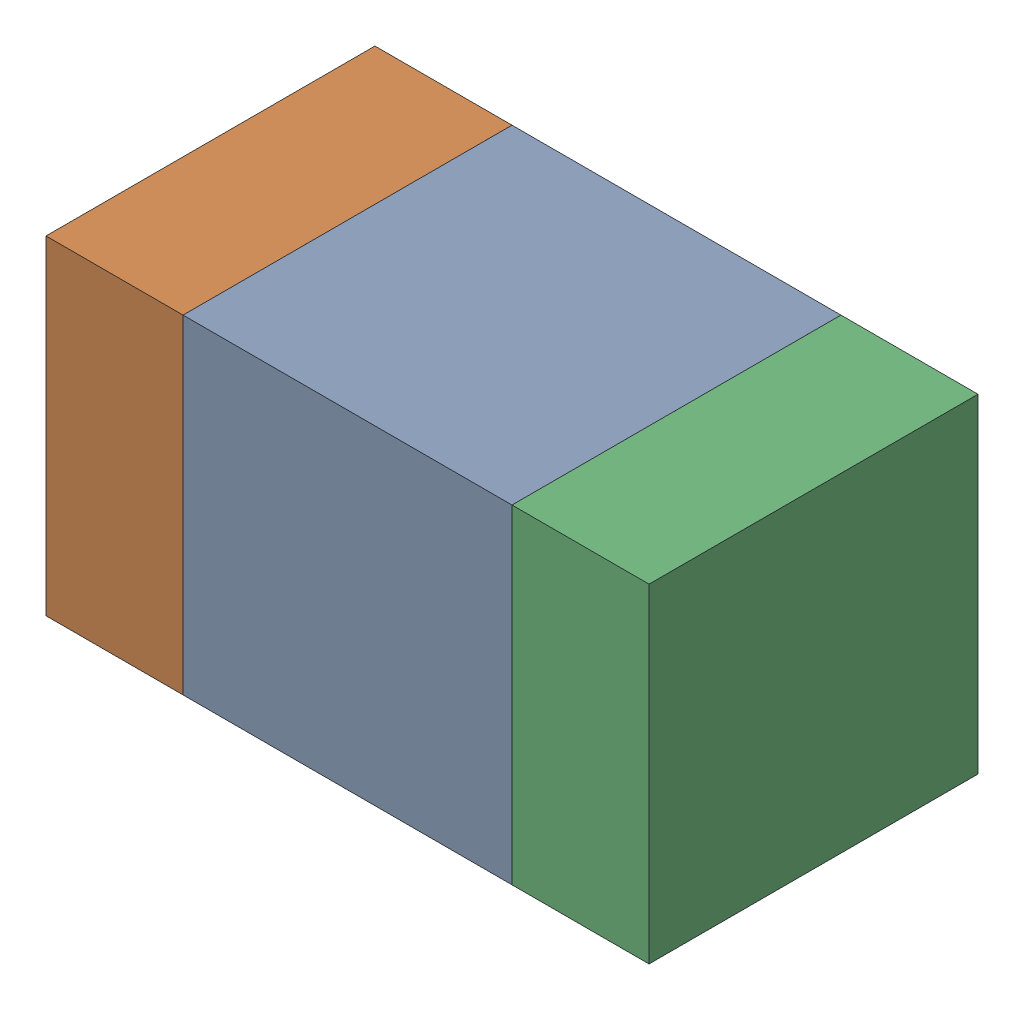
SolidWorks assembly C120_1PCB, configuration Default. Lengths in mm.
Overall size (1.1 0.6 0.6).
6 component instances, 2 part files, 0 mates.
Components (placement in the parent):
- 761606048-1: 761606048 [Default] at (114 119.3 0) size (0.6 0.6 0.6)
  - Extruded_9-1: Extruded_9 [Default] at origin size (0.6 0.6 0.6)
- 854785160-1: 854785160 [Default] at (113.575 119.3 0) size (0.25 0.6 0.6)
  - Extruded_19-1: Extruded_19 [Default] at origin size (0.25 0.6 0.6)
- 854785160-2: 854785160 [Default] at (114.425 119.3 0) size (0.25 0.6 0.6)
  - Extruded_19-1: Extruded_19 [Default] at origin size (0.25 0.6 0.6)
